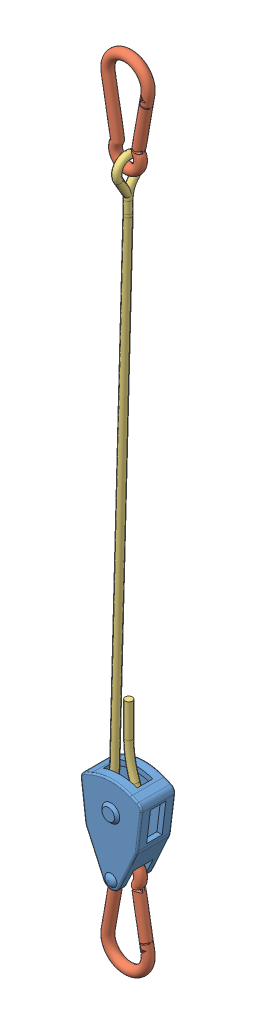
SolidWorks assembly MIS1003, configuration Default. Lengths in mm.
Overall size (29.94 392.99 19.3).
4 component instances, 3 part files, 3 mates.
Components (placement in the parent):
- MIS1003-2-1: MIS1003-2 [Default] at origin size (29.94 46.91 19.3)
- MIS1003-3-1: MIS1003-3 [Default] at (0 -31.75 0) size (24.69 52.63 4.88)
- MIS1003-3-2: MIS1003-3 [Default] at (0 336.55 0) x (1 0 0) z (0 0 -1) size (24.69 52.63 4.88)
- MIS1003-1-1: MIS1003-1 [Default] at origin size (17.27 286.13 14.73)
Mates (geometry in assembly coordinates):
- Coincident1: coincident aligned: axis of MIS1003-2-1 through (0 0 -5.842) axis (0 0 1); line of MIS1003-3-1 through (0 0 -2.6822) axis (0 0 1)
- Coincident2: coincident aligned: plane of MIS1003-3-1 through (0 -31.75 0) normal (0 0 1); plane of assembly through (0 0 0) normal (0 0 1)
- Coincident3: coincident aligned: plane of MIS1003-3-1 through (0 -31.75 0) normal (1 0 0); plane of assembly through (0 0 0) normal (1 0 0)
